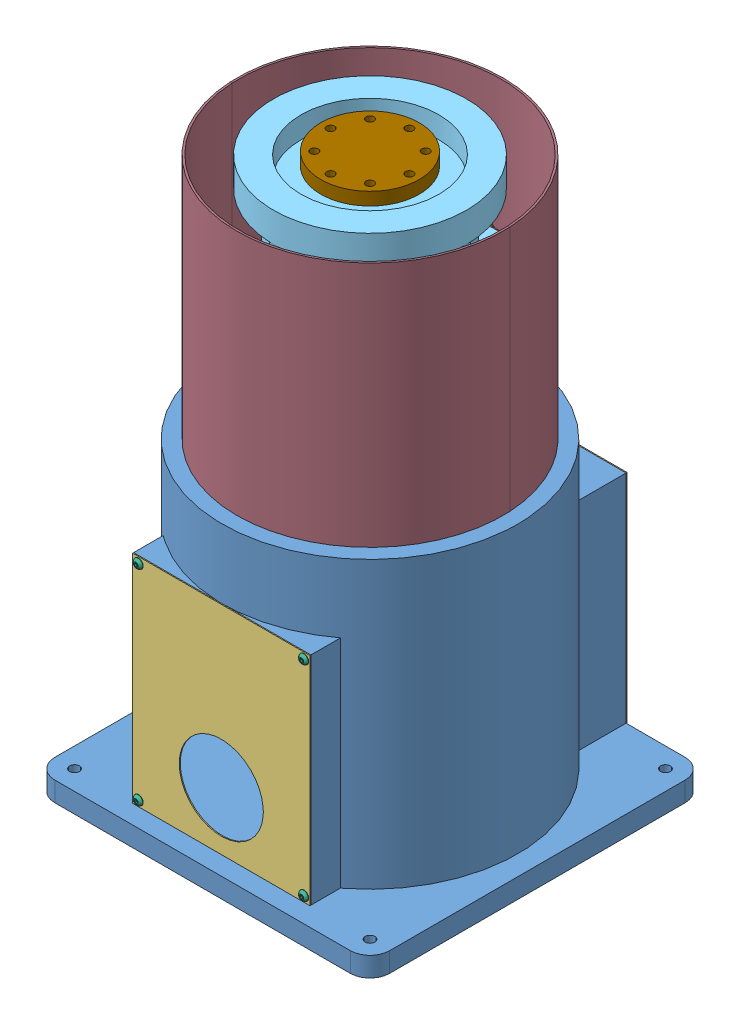
SolidWorks assembly K0, configuration Default. Lengths in mm.
Overall size (340 563 343.75).
53 component instances, 13 part files, 110 mates.
Components (placement in the parent):
- [K0]De-1: [K0]De [Default] at (-227.3224 47.5402 430.4484) x (1 0 0) z (0 1 0) size (340 340 350)
- [K0]Nắp.stp-1: [K0]Nắp.stp [Default] at (-227.3224 442.5402 312.6562) x (0 0 -1) z (1 0 0) size (1 90 110)
- [K0]Nắp_dây_điện.stp-1: [K0]Nắp_dây_điện.stp [Default] at (-227.3224 177.5402 259.4484) x (0 0 1) z (-1 0 0) size (1 220 180)
- [K0]Ốp_thân.stp-1: [K0]Ốp_thân.stp [Default] at (-227.3224 354.7114 430.4484) x (-0.251409 0 -0.967881) z (0.967881 0 -0.251409) size (270 250 135) (hidden)
- [K1]Động_cơ.stp-1: [K1]Động_cơ.stp [Default] at (-227.3224 365.5402 430.4484) x (1 0 0) z (0 1 0) size (80 90.1 217)
- [K0]Than_tru-1: [K0]Than_tru [Default] at (-227.3224 397.5402 430.4484) x (0 0 -1) z (1 0 0) size (215.79 210 196)
- [K0]Nắp_dây_điện.stp-2: [K0]Nắp_dây_điện.stp [Default] at (-227.3224 177.5402 581.4484) x (0 0 -1) z (1 0 0) size (1 220 180)
- [K0]Ốp_thân.stp-2: [K0]Ốp_thân.stp [Default] at (-227.3224 357.7103 430.4484) x (0.251409 0 0.967881) z (-0.967881 0 0.251409) size (270 250 135) (hidden)
- socket button head screw_iso-1: socket button head screw_iso [ISO 7380 - M5 x 10 - 10N] at (-311.3224 73.5402 256.6984) x (0 0 1) z (-1 0 0) size (12.75 9.5 9.5)
- socket button head screw_iso-2: socket button head screw_iso [ISO 7380 - M5 x 10 - 10N] at (-311.3224 281.5402 256.6984) x (0 0 1) z (0.308562 0.951204 0) size (12.75 9.5 9.5)
- socket button head screw_iso-5: socket button head screw_iso [ISO 7380 - M5 x 10 - 10N] at (-311.3224 73.5402 584.1984) x (0 0 -1) z (0.923728 0.383049 0) size (12.75 9.5 9.5)
- socket button head screw_iso-6: socket button head screw_iso [ISO 7380 - M5 x 10 - 10N] at (-143.3224 73.5402 256.6984) x (0 0 1) z (-1 0 0) size (12.75 9.5 9.5)
- socket button head screw_iso-7: socket button head screw_iso [ISO 7380 - M5 x 10 - 10N] at (-311.3224 281.5402 584.1984) x (0 0 -1) z (-0.381849 0.924225 0) size (12.75 9.5 9.5)
- socket button head screw_iso-8: socket button head screw_iso [ISO 7380 - M5 x 10 - 10N] at (-143.3224 281.5402 256.6984) x (0 0 1) z (-0.845509 0.533962 0) size (12.75 9.5 9.5)
- socket button head screw_iso-10: socket button head screw_iso [ISO 7380 - M5 x 10 - 10N] at (-143.3224 281.5402 256.6984) x (0 0 1) z (-0.845509 0.533962 0) size (12.75 9.5 9.5)
- socket button head screw_iso-11: socket button head screw_iso [ISO 7380 - M5 x 10 - 10N] at (-143.3224 281.5402 584.1984) x (0 0 -1) z (0.576487 0.817107 0) size (12.75 9.5 9.5)
- socket button head screw_iso-12: socket button head screw_iso [ISO 7380 - M5 x 10 - 10N] at (-143.3224 73.5402 584.1984) x (0 0 -1) z (0.576487 0.817107 0) size (12.75 9.5 9.5)
- socket head cap screw_iso-2: socket head cap screw_iso [ISO 4762 M10 x 55 - 32N] at (-163.6828 427.5402 366.8088) x (0 -1 0) z (-0.767244 0 -0.641355) size (65 16 16)
- socket head cap screw_iso-3: socket head cap screw_iso [ISO 4762 M10 x 55 - 32N] at (-290.962 427.5402 494.088) x (0 -1 0) z (0.999396 0 0.034748) size (65 16 16)
- socket head cap screw_iso-4: socket head cap screw_iso [ISO 4762 M10 x 55 - 32N] at (-163.6828 427.5402 494.088) x (0 -1 0) z (0.247627 0 0.968855) size (65 16 16)
- socket head cap screw_iso-5: socket head cap screw_iso [ISO 4762 M10 x 55 - 32N] at (-290.962 427.5402 366.8088) x (0 -1 0) z (0.695969 0 0.718072) size (65 16 16)
- hex flange nut gradea_iso-2: hex flange nut gradea_iso [ISO - 4161 - M10 - N] at (-163.6828 358.5402 494.088) x (0.598108 0 -0.801416) z (0 -1 0) size (21.8 21.8 10)
- hex flange nut gradea_iso-3: hex flange nut gradea_iso [ISO - 4161 - M10 - N] at (-290.962 358.5402 494.088) x (0.966301 0 0.257415) z (0 -1 0) size (21.8 21.8 10)
- hex flange nut gradea_iso-4: hex flange nut gradea_iso [ISO - 4161 - M10 - N] at (-290.962 358.5402 366.8088) x (0.734651 0 -0.678446) z (0 -1 0) size (21.8 21.8 10)
- hex flange nut gradea_iso-5: hex flange nut gradea_iso [ISO - 4161 - M10 - N] at (-163.6828 358.5402 366.8088) x (0.986541 0 0.163513) z (0 -1 0) size (21.8 21.8 10)
- [K0]Truc-1: [K0]Truc [Default] at (-227.3224 610.5402 430.4484) x (0 0 1) z (1 0 0) size (100 163 100)
- [K0]O_lan-1: [K0]O_lan [Default] at (-227.3224 587.5402 430.4484) x (-0.373121 0 -0.927783) z (-0.927783 0 0.373121) size (50 22 50)
- [K0]Hop_giam_toc-1: [K0]Hop_giam_toc [Default] at (-227.3224 400.5402 430.4484) size (140 70 140)
- socket head cap screw_iso-12: socket head cap screw_iso [ISO 4762 M6 x 55 - 24N] at (-183.1282 426.5402 386.2542) x (0 -1 0) z (-0.138586 0 0.99035) size (61 10 10)
- socket head cap screw_iso-13: socket head cap screw_iso [ISO 4762 M6 x 55 - 24N] at (-164.8224 426.5402 430.4484) x (0 -1 0) z (0.994449 0 0.105223) size (61 10 10)
- socket head cap screw_iso-14: socket head cap screw_iso [ISO 4762 M6 x 55 - 24N] at (-227.3224 426.5402 492.9484) x (0 -1 0) z (0 0 1) size (61 10 10)
- socket head cap screw_iso-15: socket head cap screw_iso [ISO 4762 M6 x 55 - 24N] at (-183.1282 426.5402 474.6426) x (0 -1 0) z (0 0 1) size (61 10 10)
- socket head cap screw_iso-17: socket head cap screw_iso [ISO 4762 M6 x 55 - 24N] at (-271.5166 426.5402 474.6426) x (0 -1 0) z (0 0 1) size (61 10 10)
- socket head cap screw_iso-18: socket head cap screw_iso [ISO 4762 M6 x 55 - 24N] at (-289.8224 426.5402 430.4484) x (0 -1 0) z (0 0 1) size (61 10 10)
- socket head cap screw_iso-19: socket head cap screw_iso [ISO 4762 M6 x 55 - 24N] at (-271.5166 426.5402 386.2542) x (0 -1 0) z (0 0 1) size (61 10 10)
- socket head cap screw_iso-20: socket head cap screw_iso [ISO 4762 M6 x 55 - 24N] at (-227.3224 426.5402 367.9484) x (0 -1 0) z (0 0 1) size (61 10 10)
- hex flange nut gradea_iso-20: hex flange nut gradea_iso [ISO - 4161 - M6 - N] at (-289.8224 362.5402 430.4484) x (1 0 0) z (0 -1 0) size (14.2 14.2 6)
- hex flange nut gradea_iso-21: hex flange nut gradea_iso [ISO - 4161 - M6 - N] at (-271.5166 362.5402 386.2542) x (1 0 0) z (0 -1 0) size (14.2 14.2 6)
- hex flange nut gradea_iso-22: hex flange nut gradea_iso [ISO - 4161 - M6 - N] at (-227.3224 362.5402 367.9484) x (1 0 0) z (0 -1 0) size (14.2 14.2 6)
- hex flange nut gradea_iso-23: hex flange nut gradea_iso [ISO - 4161 - M6 - N] at (-271.5166 362.5402 474.6426) x (1 0 0) z (0 -1 0) size (14.2 14.2 6)
- hex flange nut gradea_iso-24: hex flange nut gradea_iso [ISO - 4161 - M6 - N] at (-183.1282 362.5402 386.2542) x (1 0 0) z (0 -1 0) size (14.2 14.2 6)
- hex flange nut gradea_iso-25: hex flange nut gradea_iso [ISO - 4161 - M6 - N] at (-164.8224 362.5402 430.4484) x (1 0 0) z (0 -1 0) size (14.2 14.2 6)
- hex flange nut gradea_iso-26: hex flange nut gradea_iso [ISO - 4161 - M6 - N] at (-227.3224 362.5402 492.9484) x (1 0 0) z (0 -1 0) size (14.2 14.2 6)
- hex flange nut gradea_iso-27: hex flange nut gradea_iso [ISO - 4161 - M6 - N] at (-183.1282 362.5402 474.6426) x (1 0 0) z (0 -1 0) size (14.2 14.2 6)
- socket head cap screw_iso-22: socket head cap screw_iso [ISO 4762 M6 x 30 - 30N] at (-195.5026 351.5402 398.6286) x (0 1 0) z (0 0 1) size (36 10 10)
- socket head cap screw_iso-23: socket head cap screw_iso [ISO 4762 M6 x 30 - 30N] at (-195.5026 351.5402 462.2682) x (0 1 0) z (0 0 1) size (36 10 10)
- socket head cap screw_iso-24: socket head cap screw_iso [ISO 4762 M6 x 30 - 30N] at (-259.1422 351.5402 462.2682) x (0 1 0) z (0 0 1) size (36 10 10)
- socket head cap screw_iso-25: socket head cap screw_iso [ISO 4762 M6 x 30 - 30N] at (-259.1422 351.5402 398.6286) x (0 1 0) z (0 0 1) size (36 10 10)
- socket countersunk head screw_iso-4: socket countersunk head screw_iso [ISO 10642 - M5 x 8 - 8N] at (-178.8224 406.5402 308.6734) x (0 0 1) z (-0.923728 -0.383049 0) size (8 9.43 9.43)
- socket countersunk head screw_iso-5: socket countersunk head screw_iso [ISO 10642 - M5 x 8 - 8N] at (-227.3224 482.5402 308.6734) x (0 0 1) z (-0.90514 0.425113 0) size (8 9.43 9.43)
- socket countersunk head screw_iso-6: socket countersunk head screw_iso [ISO 10642 - M5 x 8 - 8N] at (-275.8224 406.5402 308.6734) x (0 0 1) z (-0.923728 -0.383049 0) size (8 9.43 9.43)
- [K0]Ốp_thân.stp-3: [K0]Ốp_thân.stp [Default] at (-227.3224 357.5402 430.4484) x (0.998566 0 -0.053544) z (0.053544 0 0.998566) size (270 250 135)
- [K0]Ốp_thân.stp-4: [K0]Ốp_thân.stp [Default] at (-227.3224 357.5402 430.4484) x (-0.998566 0 0.053544) z (-0.053544 0 -0.998566) size (270 250 135)
Mates (geometry in assembly coordinates):
- Coincident2: coincident anti-aligned: plane of [K0]De-1 through (-77.3224 67.5402 280.4484) normal (0 1 0); plane of [K0]Nắp_dây_điện.stp-1 through (-317.3224 67.5402 259.4484) normal (0 -1 0)
- Coincident3: coincident aligned: plane of [K0]De-1 through (-137.3224 287.5402 430.4484) normal (1 0 0); plane of [K0]Nắp_dây_điện.stp-1 through (-137.3224 67.5402 259.4484) normal (1 0 0)
- Concentric9: concentric aligned: cylinder of [K0]De-1 through (-227.3224 397.5402 430.4484) axis (0 -1 0) radius 130; cylinder of [K0]Than_tru-1 through (-227.3224 607.5402 430.4484) axis (0 -1 0) radius 78
- Coincident6: coincident anti-aligned: plane of [K0]De-1 through (-227.3224 397.5402 430.4484) normal (0 1 0); plane of [K0]Than_tru-1 through (-227.3224 397.5402 430.4484) normal (0 -1 0)
- Parallel5: parallel aligned: plane of [K0]Nắp_dây_điện.stp-1 through (-227.3224 177.5402 259.4484) normal (0 0 -1); plane of [K0]Than_tru-1 through (-227.3224 487.5402 312.6562) normal (0 0 -1)
- Coincident8: coincident anti-aligned: plane of [K0]De-1 through (-227.3224 287.5402 580.4484) normal (0 0 1); plane of [K0]Nắp_dây_điện.stp-2 through (-227.3224 177.5402 580.4484) normal (0 0 -1)
- Coincident9: coincident anti-aligned: plane of [K0]De-1 through (-77.3224 67.5402 280.4484) normal (0 1 0); plane of [K0]Nắp_dây_điện.stp-2 through (-137.3224 67.5402 581.4484) normal (0 -1 0)
- Coincident11: coincident anti-aligned: plane of [K0]Nắp.stp-1 through (-227.3224 442.5402 312.6562) normal (0 0 1); plane of [K0]Than_tru-1 through (-227.3224 487.5402 312.6562) normal (0 0 -1)
- Coincident12: coincident anti-aligned: plane of [K0]De-1 through (-227.3224 397.5402 430.4484) normal (0 1 0); plane of [K0]Nắp.stp-1 through (-172.3224 397.5402 312.6562) normal (0 -1 0)
- Coincident13: coincident aligned: plane of [K0]Nắp.stp-1 through (-282.3224 397.5402 312.6562) normal (-1 0 0); plane of [K0]Than_tru-1 through (-282.3224 487.5402 430.4484) normal (-1 0 0)
- Concentric10: concentric aligned: cylinder of [K0]Ốp_thân.stp-1 through (-227.3224 354.7114 430.4484) axis (0 1 0) radius 133; cylinder of [K0]Than_tru-1 through (-227.3224 300.3543 430.4484) axis (0 1 0) radius 98
- Concentric12: concentric aligned: cylinder of [K0]De-1 through (-227.3224 231.6163 430.4484) axis (0 1 0) radius 32.5; cylinder of [K1]Động_cơ.stp-1 through (-227.3224 387.0402 430.4484) axis (0 1 0) radius 9.5
- Parallel6: parallel aligned: plane of [K1]Động_cơ.stp-1 through (-227.3224 299.0402 470.4484) normal (0 0 1); plane of [K0]Nắp_dây_điện.stp-2 through (-227.3224 177.5402 581.4484) normal (0 0 1)
- Coincident17: coincident anti-aligned: plane of [K0]De-1 through (-227.3224 368.5402 430.4484) normal (0 -1 0); plane of [K1]Động_cơ.stp-1 through (-227.3224 368.5402 430.4484) normal (0 1 0)
- Concentric14: concentric anti-aligned: cylinder of [K0]De-1 through (-227.3224 397.5402 430.4484) axis (0 -1 0) radius 130; cylinder of [K0]Ốp_thân.stp-2 through (-227.3224 357.7103 430.4484) axis (0 1 0) radius 133
- Coincident19: coincident anti-aligned: plane of [K0]Ốp_thân.stp-1 through (-260.7598 354.7114 301.7203) normal (0.967881 0 -0.251409); plane of [K0]Ốp_thân.stp-2 through (-261.2626 357.7103 299.7845) normal (-0.967881 0 0.251409)
- Concentric18: concentric anti-aligned: cylinder of [K0]Nắp_dây_điện.stp-1 through (-143.3224 281.5402 -23.8068) axis (0 0 1) radius 2.5; cylinder of socket button head screw_iso-8 through (-143.3224 281.5402 256.6984) axis (0 0 -1) radius 2.5
- Coincident22: coincident anti-aligned: plane of [K0]Nắp_dây_điện.stp-1 through (-227.3224 177.5402 259.4484) normal (0 0 -1); plane of socket button head screw_iso-8 through (-141.9875 283.6539 259.4484) normal (0 0 1)
- Concentric19: concentric anti-aligned: cylinder of [K0]Nắp_dây_điện.stp-1 through (-311.3224 281.5402 -23.8068) axis (0 0 1) radius 2.5; cylinder of socket button head screw_iso-2 through (-311.3224 281.5402 256.6984) axis (0 0 -1) radius 2.5
- Coincident23: coincident anti-aligned: plane of [K0]Nắp_dây_điện.stp-1 through (-227.3224 177.5402 259.4484) normal (0 0 -1); plane of socket button head screw_iso-2 through (-308.9444 280.7688 259.4484) normal (0 0 1)
- Concentric20: concentric anti-aligned: cylinder of [K0]Nắp_dây_điện.stp-1 through (-143.3224 73.5402 -23.8068) axis (0 0 1) radius 2.5; cylinder of socket button head screw_iso-6 through (-143.3224 73.5402 256.6984) axis (0 0 -1) radius 2.5
- Coincident24: coincident anti-aligned: plane of [K0]Nắp_dây_điện.stp-1 through (-227.3224 177.5402 259.4484) normal (0 0 -1); plane of socket button head screw_iso-6 through (-143.3224 76.0402 259.4484) normal (0 0 1)
- Concentric21: concentric anti-aligned: cylinder of [K0]Nắp_dây_điện.stp-1 through (-311.3224 73.5402 -23.8068) axis (0 0 1) radius 2.5; cylinder of socket button head screw_iso-1 through (-311.3224 73.5402 256.6984) axis (0 0 -1) radius 2.5
- Coincident25: coincident anti-aligned: plane of [K0]Nắp_dây_điện.stp-1 through (-227.3224 177.5402 259.4484) normal (0 0 -1); plane of socket button head screw_iso-1 through (-311.3224 76.0402 259.4484) normal (0 0 1)
- Coincident26: coincident anti-aligned: plane of [K0]De-1 through (-77.3224 67.5402 260.4484) normal (0 0 -1); plane of [K0]Nắp_dây_điện.stp-1 through (-227.3224 177.5402 260.4484) normal (0 0 1)
- Concentric22: concentric anti-aligned: cylinder of [K0]Nắp_dây_điện.stp-2 through (-311.3224 281.5402 864.7036) axis (0 0 -1) radius 2.5; cylinder of socket button head screw_iso-7 through (-311.3224 281.5402 584.1984) axis (0 0 1) radius 2.5
- Coincident27: coincident anti-aligned: plane of [K0]Nắp_dây_điện.stp-2 through (-227.3224 177.5402 581.4484) normal (0 0 1); plane of socket button head screw_iso-7 through (-313.633 280.5855 581.4484) normal (0 0 -1)
- Concentric24: concentric anti-aligned: cylinder of [K0]Nắp_dây_điện.stp-2 through (-143.3224 281.5402 864.7036) axis (0 0 -1) radius 2.5; cylinder of socket button head screw_iso-11 through (-143.3224 281.5402 584.1984) axis (0 0 1) radius 2.5
- Coincident29: coincident anti-aligned: plane of [K0]Nắp_dây_điện.stp-2 through (-227.3224 177.5402 581.4484) normal (0 0 1); plane of socket button head screw_iso-11 through (-145.3652 282.9814 581.4484) normal (0 0 -1)
- Concentric27: concentric anti-aligned: cylinder of [K0]Nắp_dây_điện.stp-2 through (-311.3224 73.5402 864.7036) axis (0 0 -1) radius 2.5; cylinder of socket button head screw_iso-5 through (-311.3224 73.5402 584.1984) axis (0 0 1) radius 2.5
- Concentric28: concentric anti-aligned: cylinder of [K0]Nắp_dây_điện.stp-2 through (-143.3224 73.5402 864.7036) axis (0 0 -1) radius 2.5; cylinder of socket button head screw_iso-12 through (-143.3224 73.5402 584.1984) axis (0 0 1) radius 2.5
- Coincident31: coincident anti-aligned: plane of [K0]Nắp_dây_điện.stp-2 through (-227.3224 177.5402 581.4484) normal (0 0 1); plane of socket button head screw_iso-12 through (-145.3652 74.9814 581.4484) normal (0 0 -1)
- Coincident32: coincident anti-aligned: plane of [K0]Nắp_dây_điện.stp-2 through (-227.3224 177.5402 581.4484) normal (0 0 1); plane of socket button head screw_iso-5 through (-312.28 75.8495 581.4484) normal (0 0 -1)
- Coincident33: coincident aligned: plane of [K0]De-1 through (-137.3224 287.5402 430.4484) normal (1 0 0); plane of [K0]Nắp_dây_điện.stp-2 through (-137.3224 287.5402 581.4484) normal (1 0 0)
- Concentric29: concentric anti-aligned: cylinder of [K0]Than_tru-1 through (-163.6828 431.6823 366.8088) axis (0 -1 0) radius 5; cylinder of socket head cap screw_iso-2 through (-163.6828 459.2902 366.8088) axis (0 1 0) radius 5
- Coincident34: coincident anti-aligned: plane of [K0]Than_tru-1 through (-227.3224 417.5402 430.4484) normal (0 1 0); plane of socket head cap screw_iso-2 through (-168.8136 417.5402 372.9468) normal (0 -1 0)
- Concentric30: concentric anti-aligned: cylinder of [K0]Than_tru-1 through (-163.6828 431.6823 494.088) axis (0 -1 0) radius 5; cylinder of socket head cap screw_iso-4 through (-163.6828 459.2902 494.088) axis (0 1 0) radius 5
- Concentric31: concentric anti-aligned: cylinder of [K0]Than_tru-1 through (-290.962 431.6823 366.8088) axis (0 -1 0) radius 5; cylinder of socket head cap screw_iso-5 through (-290.962 459.2902 366.8088) axis (0 1 0) radius 5
- Concentric33: concentric anti-aligned: cylinder of [K0]Than_tru-1 through (-290.962 431.6823 494.088) axis (0 -1 0) radius 5; cylinder of socket head cap screw_iso-3 through (-290.962 459.2902 494.088) axis (0 1 0) radius 5
- Coincident35: coincident anti-aligned: plane of [K0]Than_tru-1 through (-227.3224 417.5402 430.4484) normal (0 1 0); plane of socket head cap screw_iso-3 through (-290.684 417.5402 486.0929) normal (0 -1 0)
- Coincident37: coincident anti-aligned: plane of [K0]Than_tru-1 through (-227.3224 417.5402 430.4484) normal (0 1 0); plane of socket head cap screw_iso-4 through (-155.9319 417.5402 492.107) normal (0 -1 0)
- Concentric34: concentric anti-aligned: cylinder of socket head cap screw_iso-4 through (-163.6828 459.2902 494.088) axis (0 1 0) radius 5; cylinder of hex flange nut gradea_iso-2 through (-163.6828 368.5402 494.088) axis (0 -1 0) radius 4.25
- Concentric35: concentric anti-aligned: cylinder of socket head cap screw_iso-3 through (-290.962 459.2902 494.088) axis (0 1 0) radius 5; cylinder of hex flange nut gradea_iso-3 through (-290.962 368.5402 494.088) axis (0 -1 0) radius 4.25
- Concentric36: concentric anti-aligned: cylinder of socket head cap screw_iso-5 through (-290.962 459.2902 366.8088) axis (0 1 0) radius 5; cylinder of hex flange nut gradea_iso-4 through (-290.962 368.5402 366.8088) axis (0 -1 0) radius 4.25
- Concentric37: concentric anti-aligned: cylinder of socket head cap screw_iso-2 through (-163.6828 459.2902 366.8088) axis (0 1 0) radius 5; cylinder of hex flange nut gradea_iso-5 through (-163.6828 368.5402 366.8088) axis (0 -1 0) radius 4.25
- Coincident38: coincident anti-aligned: plane of [K0]Than_tru-1 through (-227.3224 417.5402 430.4484) normal (0 1 0); plane of socket head cap screw_iso-5 through (-285.2174 417.5402 361.2411) normal (0 -1 0)
- Coincident40: coincident aligned: plane of hex flange nut gradea_iso-3 through (-305.4565 368.5402 490.2268) normal (0 1 0); plane of hex flange nut gradea_iso-4 through (-301.9818 368.5402 376.9855) normal (0 1 0)
- Coincident41: coincident aligned: plane of hex flange nut gradea_iso-4 through (-301.9818 368.5402 376.9855) normal (0 1 0); plane of hex flange nut gradea_iso-5 through (-178.4809 368.5402 364.3561) normal (0 1 0)
- Coincident42: coincident aligned: plane of hex flange nut gradea_iso-2 through (-172.6544 368.5402 506.1093) normal (0 1 0); plane of hex flange nut gradea_iso-5 through (-178.4809 368.5402 364.3561) normal (0 1 0)
- Coincident44: coincident anti-aligned: plane of [K0]De-1 through (-227.3224 368.5402 430.4484) normal (0 -1 0); plane of hex flange nut gradea_iso-3 through (-305.4565 368.5402 490.2268) normal (0 1 0)
- Concentric43: concentric aligned: cylinder of [K0]Truc-1 through (-227.3224 610.5402 430.4484) axis (0 1 0) radius 10; cylinder of [K0]O_lan-1 through (-227.3224 565.5402 430.4484) axis (0 1 0) radius 10
- Concentric45: concentric aligned: cylinder of [K0]Than_tru-1 through (-227.3224 565.5402 430.4484) axis (0 1 0) radius 25; cylinder of [K0]Truc-1 through (-227.3224 610.5402 430.4484) axis (0 1 0) radius 10
- Concentric46: concentric aligned: cylinder of [K0]Than_tru-1 through (-227.3224 565.5402 430.4484) axis (0 1 0) radius 25; cylinder of [K0]O_lan-1 through (-227.3224 565.5402 430.4484) axis (0 1 0) radius 25
- Coincident49: coincident anti-aligned: plane of [K0]Than_tru-1 through (-227.3224 565.5402 430.4484) normal (0 1 0); plane of [K0]O_lan-1 through (-227.3224 565.5402 430.4484) normal (0 -1 0)
- Coincident50: coincident anti-aligned: plane of [K0]Truc-1 through (-252.3224 587.5402 430.4484) normal (0 -1 0); plane of [K0]O_lan-1 through (-227.3224 587.5402 430.4484) normal (0 1 0)
- Concentric47: concentric anti-aligned: cylinder of [K1]Động_cơ.stp-1 through (-227.3224 387.0402 430.4484) axis (0 1 0) radius 9.5; cylinder of [K0]Hop_giam_toc-1 through (-227.3224 420.5402 430.4484) axis (0 -1 0) radius 10
- Distance1: distance = 35 mm anti-aligned: plane of [K0]Hop_giam_toc-1 through (-227.3224 400.5402 430.4484) normal (0 -1 0); plane of [K1]Động_cơ.stp-1 through (-227.3224 365.5402 430.4484) normal (0 1 0)
- Concentric50: concentric anti-aligned: cylinder of [K0]De-1 through (-271.5166 354.398 386.2542) axis (0 1 0) radius 3; cylinder of [K0]Hop_giam_toc-1 through (-271.5166 470.5402 386.2542) axis (0 -1 0) radius 3
- Concentric54: concentric anti-aligned: cylinder of [K0]Hop_giam_toc-1 through (-183.1282 470.5402 386.2542) axis (0 -1 0) radius 3; cylinder of socket head cap screw_iso-12 through (-183.1282 458.2902 386.2542) axis (0 1 0) radius 5
- Coincident61: coincident anti-aligned: plane of [K0]Hop_giam_toc-1 through (-227.3224 420.5402 430.4484) normal (0 1 0); plane of socket head cap screw_iso-12 through (-178.1765 420.5402 386.9472) normal (0 -1 0)
- Concentric55: concentric anti-aligned: cylinder of [K0]Hop_giam_toc-1 through (-164.8224 470.5402 430.4484) axis (0 -1 0) radius 3; cylinder of socket head cap screw_iso-13 through (-164.8224 458.2902 430.4484) axis (0 1 0) radius 5
- Coincident62: coincident anti-aligned: plane of [K0]Hop_giam_toc-1 through (-227.3224 420.5402 430.4484) normal (0 1 0); plane of socket head cap screw_iso-13 through (-164.2963 420.5402 425.4762) normal (0 -1 0)
- Concentric56: concentric anti-aligned: cylinder of [K0]Hop_giam_toc-1 through (-227.3224 470.5402 492.9484) axis (0 -1 0) radius 3; cylinder of socket head cap screw_iso-14 through (-227.3224 458.2902 492.9484) axis (0 1 0) radius 5
- Coincident63: coincident anti-aligned: plane of [K0]Hop_giam_toc-1 through (-227.3224 420.5402 430.4484) normal (0 1 0); plane of socket head cap screw_iso-14 through (-222.3224 420.5402 492.9484) normal (0 -1 0)
- Concentric57: concentric anti-aligned: cylinder of [K0]Hop_giam_toc-1 through (-183.1282 470.5402 474.6426) axis (0 -1 0) radius 3; cylinder of socket head cap screw_iso-15 through (-183.1282 458.2902 474.6426) axis (0 1 0) radius 5
- Coincident64: coincident anti-aligned: plane of [K0]Hop_giam_toc-1 through (-227.3224 420.5402 430.4484) normal (0 1 0); plane of socket head cap screw_iso-15 through (-178.1282 420.5402 474.6426) normal (0 -1 0)
- Concentric59: concentric anti-aligned: cylinder of [K0]Hop_giam_toc-1 through (-271.5166 470.5402 474.6426) axis (0 -1 0) radius 3; cylinder of socket head cap screw_iso-17 through (-271.5166 458.2902 474.6426) axis (0 1 0) radius 5
- Coincident65: coincident anti-aligned: plane of [K0]Hop_giam_toc-1 through (-227.3224 420.5402 430.4484) normal (0 1 0); plane of socket head cap screw_iso-17 through (-266.5166 420.5402 474.6426) normal (0 -1 0)
- Concentric60: concentric anti-aligned: cylinder of [K0]Hop_giam_toc-1 through (-289.8224 470.5402 430.4484) axis (0 -1 0) radius 3; cylinder of socket head cap screw_iso-18 through (-289.8224 458.2902 430.4484) axis (0 1 0) radius 5
- Coincident66: coincident anti-aligned: plane of [K0]Hop_giam_toc-1 through (-227.3224 420.5402 430.4484) normal (0 1 0); plane of socket head cap screw_iso-18 through (-284.8224 420.5402 430.4484) normal (0 -1 0)
- Concentric61: concentric anti-aligned: cylinder of [K0]Hop_giam_toc-1 through (-271.5166 470.5402 386.2542) axis (0 -1 0) radius 3; cylinder of socket head cap screw_iso-19 through (-271.5166 458.2902 386.2542) axis (0 1 0) radius 5
- Coincident67: coincident anti-aligned: plane of [K0]Hop_giam_toc-1 through (-227.3224 420.5402 430.4484) normal (0 1 0); plane of socket head cap screw_iso-19 through (-266.5166 420.5402 386.2542) normal (0 -1 0)
- Concentric62: concentric anti-aligned: cylinder of [K0]Hop_giam_toc-1 through (-227.3224 470.5402 367.9484) axis (0 -1 0) radius 3; cylinder of socket head cap screw_iso-20 through (-227.3224 458.2902 367.9484) axis (0 1 0) radius 5
- Coincident68: coincident anti-aligned: plane of [K0]Hop_giam_toc-1 through (-227.3224 420.5402 430.4484) normal (0 1 0); plane of socket head cap screw_iso-20 through (-222.3224 420.5402 367.9484) normal (0 -1 0)
- Concentric75: concentric anti-aligned: cylinder of [K0]De-1 through (-289.8224 354.398 430.4484) axis (0 1 0) radius 3; cylinder of hex flange nut gradea_iso-20 through (-289.8224 387.5777 430.4484) axis (0 -1 0) radius 3
- Coincident79: coincident anti-aligned: plane of [K0]De-1 through (-227.3224 368.5402 430.4484) normal (0 -1 0); plane of hex flange nut gradea_iso-20 through (-299.8224 368.5402 430.4484) normal (0 1 0)
- Concentric76: concentric anti-aligned: cylinder of [K0]De-1 through (-271.5166 354.398 386.2542) axis (0 1 0) radius 3; cylinder of hex flange nut gradea_iso-21 through (-271.5166 387.5777 386.2542) axis (0 -1 0) radius 3
- Coincident80: coincident anti-aligned: plane of [K0]De-1 through (-227.3224 368.5402 430.4484) normal (0 -1 0); plane of hex flange nut gradea_iso-21 through (-281.5166 368.5402 386.2542) normal (0 1 0)
- Concentric77: concentric anti-aligned: cylinder of [K0]De-1 through (-227.3224 354.398 367.9484) axis (0 1 0) radius 3; cylinder of hex flange nut gradea_iso-22 through (-227.3224 387.5777 367.9484) axis (0 -1 0) radius 3
- Coincident81: coincident anti-aligned: plane of [K0]De-1 through (-227.3224 368.5402 430.4484) normal (0 -1 0); plane of hex flange nut gradea_iso-22 through (-237.3224 368.5402 367.9484) normal (0 1 0)
- Concentric78: concentric anti-aligned: cylinder of [K0]De-1 through (-271.5166 354.398 474.6426) axis (0 1 0) radius 3; cylinder of hex flange nut gradea_iso-23 through (-271.5166 387.5777 474.6426) axis (0 -1 0) radius 3
- Coincident82: coincident anti-aligned: plane of [K0]De-1 through (-227.3224 368.5402 430.4484) normal (0 -1 0); plane of hex flange nut gradea_iso-23 through (-281.5166 368.5402 474.6426) normal (0 1 0)
- Concentric79: concentric anti-aligned: cylinder of [K0]De-1 through (-183.1282 354.398 386.2542) axis (0 1 0) radius 3; cylinder of hex flange nut gradea_iso-24 through (-183.1282 387.5777 386.2542) axis (0 -1 0) radius 3
- Coincident83: coincident anti-aligned: plane of [K0]De-1 through (-227.3224 368.5402 430.4484) normal (0 -1 0); plane of hex flange nut gradea_iso-24 through (-193.1282 368.5402 386.2542) normal (0 1 0)
- Concentric80: concentric anti-aligned: cylinder of [K0]De-1 through (-164.8224 354.398 430.4484) axis (0 1 0) radius 3; cylinder of hex flange nut gradea_iso-25 through (-164.8224 387.5777 430.4484) axis (0 -1 0) radius 3
- Coincident84: coincident anti-aligned: plane of [K0]De-1 through (-227.3224 368.5402 430.4484) normal (0 -1 0); plane of hex flange nut gradea_iso-25 through (-174.8224 368.5402 430.4484) normal (0 1 0)
- Concentric81: concentric anti-aligned: cylinder of [K0]De-1 through (-227.3224 354.398 492.9484) axis (0 1 0) radius 3; cylinder of hex flange nut gradea_iso-26 through (-227.3224 387.5777 492.9484) axis (0 -1 0) radius 3
- Coincident85: coincident anti-aligned: plane of [K0]De-1 through (-227.3224 368.5402 430.4484) normal (0 -1 0); plane of hex flange nut gradea_iso-26 through (-237.3224 368.5402 492.9484) normal (0 1 0)
- Concentric82: concentric anti-aligned: cylinder of [K0]De-1 through (-183.1282 354.398 474.6426) axis (0 1 0) radius 3; cylinder of hex flange nut gradea_iso-27 through (-183.1282 387.5777 474.6426) axis (0 -1 0) radius 3
- Coincident86: coincident anti-aligned: plane of [K0]De-1 through (-227.3224 368.5402 430.4484) normal (0 -1 0); plane of hex flange nut gradea_iso-27 through (-193.1282 368.5402 474.6426) normal (0 1 0)
- Concentric83: concentric aligned: cylinder of [K1]Động_cơ.stp-1 through (-195.5026 361.5402 398.6286) axis (0 -1 0) radius 3.3; cylinder of socket head cap screw_iso-22 through (-195.5026 319.7902 398.6286) axis (0 -1 0) radius 5
- Coincident87: coincident anti-aligned: plane of [K1]Động_cơ.stp-1 through (-194.6624 357.5402 397.7884) normal (0 -1 0); plane of socket head cap screw_iso-22 through (-200.5026 357.5402 398.6286) normal (0 1 0)
- Concentric84: concentric aligned: cylinder of [K1]Động_cơ.stp-1 through (-195.5026 361.5402 462.2682) axis (0 -1 0) radius 3.3; cylinder of socket head cap screw_iso-23 through (-195.5026 319.7902 462.2682) axis (0 -1 0) radius 5
- Coincident88: coincident anti-aligned: plane of [K1]Động_cơ.stp-1 through (-194.6624 357.5402 463.1084) normal (0 -1 0); plane of socket head cap screw_iso-23 through (-200.5026 357.5402 462.2682) normal (0 1 0)
- Concentric85: concentric aligned: cylinder of [K1]Động_cơ.stp-1 through (-259.1422 361.5402 462.2682) axis (0 -1 0) radius 3.3; cylinder of socket head cap screw_iso-24 through (-259.1422 319.7902 462.2682) axis (0 -1 0) radius 5
- Coincident89: coincident anti-aligned: plane of [K1]Động_cơ.stp-1 through (-259.9824 357.5402 463.1084) normal (0 -1 0); plane of socket head cap screw_iso-24 through (-264.1422 357.5402 462.2682) normal (0 1 0)
- Concentric86: concentric aligned: cylinder of [K1]Động_cơ.stp-1 through (-259.1422 361.5402 398.6286) axis (0 -1 0) radius 3.3; cylinder of socket head cap screw_iso-25 through (-259.1422 319.7902 398.6286) axis (0 -1 0) radius 5
- Coincident90: coincident anti-aligned: plane of [K1]Động_cơ.stp-1 through (-259.9824 357.5402 397.7884) normal (0 -1 0); plane of socket head cap screw_iso-25 through (-264.1422 357.5402 398.6286) normal (0 1 0)
- Concentric87: concentric aligned: cylinder of [K0]Nắp.stp-1 through (-227.3224 482.5402 453.7864) axis (0 0 -1) radius 2.5; cylinder of socket countersunk head screw_iso-5 through (-227.3224 482.5402 308.6734) axis (0 0 -1) radius 2.5
- Tangent1: tangent anti-aligned: plane of [K0]Nắp.stp-1 through (-227.3224 442.5402 311.6562) normal (0 0 -1); torus of socket countersunk head screw_iso-5
- Coincident91: coincident aligned: plane of socket countersunk head screw_iso-4 through (-178.8224 406.5402 308.6734) normal (0 0 -1); plane of socket countersunk head screw_iso-5 through (-227.3224 482.5402 308.6734) normal (0 0 -1)
- Coincident92: coincident aligned: plane of socket countersunk head screw_iso-4 through (-178.8224 406.5402 308.6734) normal (0 0 -1); plane of socket countersunk head screw_iso-6 through (-275.8224 406.5402 308.6734) normal (0 0 -1)
- Concentric88: concentric aligned: cylinder of [K0]Nắp.stp-1 through (-275.8224 406.5402 453.7864) axis (0 0 -1) radius 2.5; cylinder of socket countersunk head screw_iso-6 through (-275.8224 406.5402 308.6734) axis (0 0 -1) radius 2.5
- Concentric90: concentric aligned: cylinder of [K0]Nắp.stp-1 through (-178.8224 406.5402 453.7864) axis (0 0 -1) radius 2.5; cylinder of socket countersunk head screw_iso-4 through (-178.8224 406.5402 308.6734) axis (0 0 -1) radius 2.5
- Parallel10: parallel anti-aligned: plane of [K0]Nắp_dây_điện.stp-2 through (-227.3224 177.5402 581.4484) normal (0 0 1); plane of [K0]Truc-1 through (-277.3234 610.5402 432.4484) normal (0 0 -1)
- Coincident93: coincident anti-aligned: plane of [K0]De-1 through (-227.3224 357.5402 430.4484) normal (0 1 0); plane of [K0]Ốp_thân.stp-3 through (-230.9366 357.5402 363.0452) normal (0 -1 0)
- Concentric91: concentric aligned: circle of [K0]De-1; circle of [K0]Ốp_thân.stp-3
- Coincident94: coincident anti-aligned: plane of [K0]Ốp_thân.stp-3 through (-94.5132 357.5402 423.3271) normal (0.053544 0 0.998566); plane of [K0]Ốp_thân.stp-4 through (-92.516 357.5402 423.22) normal (-0.053544 0 -0.998566)
- Concentric92: concentric anti-aligned: circle of [K0]De-1; circle of [K0]Ốp_thân.stp-4
- Coincident95: coincident anti-aligned: plane of [K0]De-1 through (-227.3224 357.5402 430.4484) normal (0 1 0); plane of [K0]Ốp_thân.stp-4 through (-223.7082 357.5402 497.8516) normal (0 -1 0)
